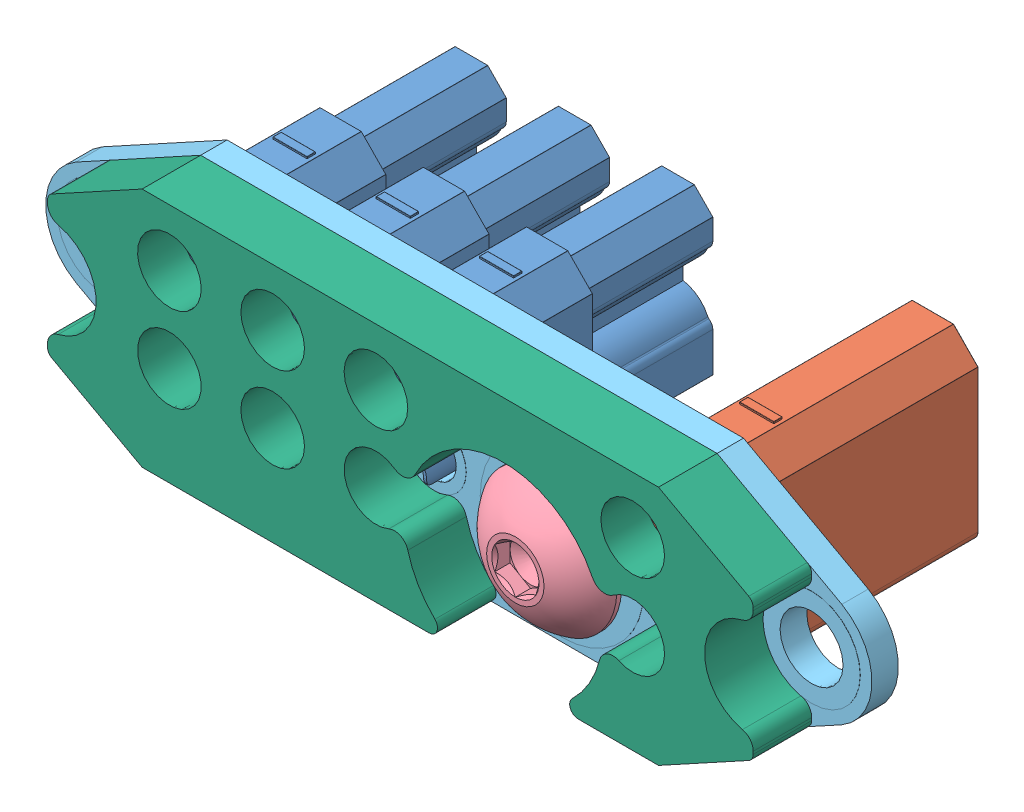
SolidWorks assembly just cuz_SwitchBoard, configuration Default. Lengths in mm.
Overall size (48 14 17.55).
9 component instances, 6 part files, 0 mates.
Components (placement in the parent):
- just cuz_SwitchBoard.stp-1: just cuz_SwitchBoard.stp [Default] at origin size (48 14 17.55)
  - XT30_Female.stp-1: XT30_Female.stp [Default] at (-4.7913 -1.9356 -6.5462) x (-1 0 0) z (0 0 -1) size (5.25 10.45 15.6)
  - XT30_Male.stp-1: XT30_Male.stp [Default] at (4.8749 -1.9112 -14.0462) size (5.25 10.45 15.5)
  - 8-32 PEM Nut Insert.stp-1: 8-32 PEM Nut Insert.stp [Default] at (0 0 -4.0856) x (1 0 0) z (0 -1 0) size (8.64 3.94 8.64)
  - XT30_Female.stp-2: XT30_Female.stp [Default] at (-10.7913 -1.9356 -6.5462) x (-1 0 0) z (0 0 -1) size (5.25 10.45 15.6)
  - XT30_Female.stp-3: XT30_Female.stp [Default] at (-16.7913 -1.9356 -6.5462) x (-1 0 0) z (0 0 -1) size (5.25 10.45 15.6)
  - 8-32 3-16 NO THREADS_ Button Head Hex Drive Screw.stp-1: 8-32 3-16 NO THREADS_ Button Head Hex Drive Screw.stp [Default] at (0 0 -0.7667) x (-1 0 0) z (0 0 1) size (7.92 7.92 6.97)
  - Switch PD Board V1.3 Bottom Connectors.stp-1: Switch PD Board V1.3 Bottom Connectors.stp [Default] at origin size (48 14 1.56)
  - Switch PD Board V1.3 Bottom Connectors-0.stp-1: Switch PD Board V1.3 Bottom Connectors-0.stp [Default] at origin size (41 14 3.4)
